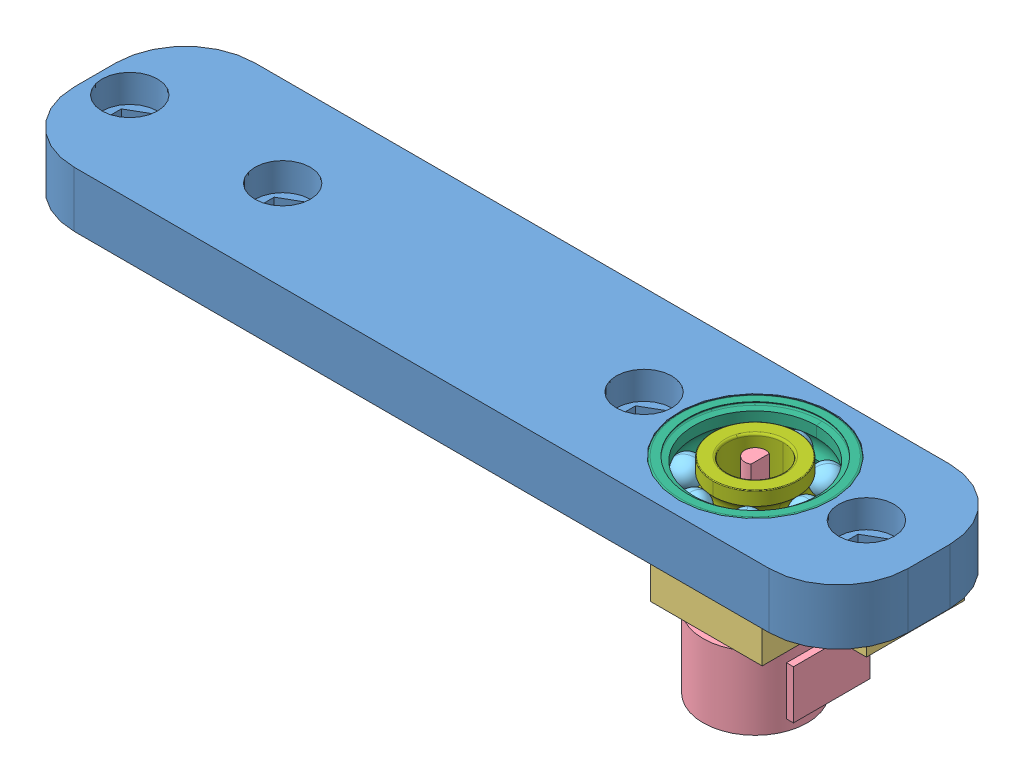
SolidWorks assembly sub_assy_robot_arm_link1, configuration Default. Lengths in mm.
Overall size (120 31 26).
14 component instances, 7 part files, 11 mates.
Components (placement in the parent):
- 2D_robotArm_link1_v1-1: 2D_robotArm_link1_v1 [Default] at origin size (120 8 26)
- robot_arm_link_bearing_insert_mk1-1: robot_arm_link_bearing_insert_mk1 [Default] at (-44 0 0) x (1 0 0) z (0 0 -1) size (30 9 11.5)
- DfRobot_stepper_FIT0503_mount_v3-1: DfRobot_stepper_FIT0503_mount_v3 [Default] at (35 0 0) x (1 0 0) z (0 0 -1) size (46.1 10.6 14.1)
- Df_Robot_stepper_FIT0503-1: Df_Robot_stepper_FIT0503 [Default] at (35 -2 0) x (-1 0 0) z (0 0 1) size (16 31 15.5)
- 608_Z-1: 608_Z [Default] at (35 8 0) x (0 -1 0) z (0 0 1) size (7 22 22)
  - 608_Z_11-1: 608_Z_11 [Default] x (1 0 0) z (0 -0.781831 0.62349) size (3.97 3.97 3.97)
  - 608_Z_11-2: 608_Z_11 [Default] x (1 0 0) z (0 -0.974928 -0.222521) size (3.97 3.97 3.97)
  - 608_Z_11-3: 608_Z_11 [Default] x (1 0 0) z (0 -0.433884 -0.900969) size (3.97 3.97 3.97)
  - 608_Z_11-4: 608_Z_11 [Default] x (1 0 0) z (0 0.433884 -0.900969) size (3.97 3.97 3.97)
  - 608_Z_11-5: 608_Z_11 [Default] x (1 0 0) z (0 0.974928 -0.222521) size (3.97 3.97 3.97)
  - 608_Z_11-6: 608_Z_11 [Default] x (1 0 0) z (0 0.781831 0.62349) size (3.97 3.97 3.97)
  - 608_Z_11-7: 608_Z_11 [Default] at origin size (3.97 3.97 3.97)
  - 608_Z_19-1: 608_Z_19 [Default] at origin size (7 22 22)
  - 608_Z_21-1: 608_Z_21 [Default] at origin size (7 19.2 19.2)
Mates (geometry in assembly coordinates):
- Coincident1: coincident aligned: line of 2D_robotArm_link1_v1-1 through (4 -33 4) axis (0 0 1); line of robot_arm_link_bearing_insert_mk1-1 through (2 -33 -2) axis (0 0 1)
- Coincident2: coincident aligned: line of 2D_robotArm_link1_v1-1 through (4 -55 4) axis (0 0 1); line of robot_arm_link_bearing_insert_mk1-1 through (2 -55 -2) axis (0 0 1)
- Coincident3: coincident anti-aligned: plane of 2D_robotArm_link1_v1-1 through (0 0 0) normal (0 -1 0); plane of robot_arm_link_bearing_insert_mk1-1 through (-44 0 0) normal (0 1 0)
- Coincident11: coincident: line of assembly; line of assembly; axis of 2D_robotArm_link1_v1-1 through (4 51 4) axis (0 0 1); axis of DfRobot_stepper_FIT0503_mount_v3-1 through (51 -2 0) axis (0 1 0)
- Coincident12: coincident: plane of 2D_robotArm_link1_v1-1 through (0 0 0) normal (0 -1 0); plane of DfRobot_stepper_FIT0503_mount_v3-1 through (35 0 0) normal (0 1 0)
- Coincident14: coincident aligned: line of 2D_robotArm_link1_v1-1 through (1.8 19 0) axis (0 0 1); line of DfRobot_stepper_FIT0503_mount_v3-1 through (19 -2 0) axis (0 1 0)
- Coincident15: coincident: line of assembly; line of assembly; axis of DfRobot_stepper_FIT0503_mount_v3-1 through (39.5 -2 0) axis (0 1 0); axis of Df_Robot_stepper_FIT0503-1 through (39.5 -35.2356 0) axis (0 1 0)
- Coincident16: coincident: line of assembly; line of assembly; axis of DfRobot_stepper_FIT0503_mount_v3-1 through (30.5 -2 0) axis (0 1 0); axis of Df_Robot_stepper_FIT0503-1 through (30.5 -4 0) axis (0 1 0)
- Coincident17: coincident anti-aligned: plane of DfRobot_stepper_FIT0503_mount_v3-1 through (35 -2 0) normal (0 -1 0); plane of Df_Robot_stepper_FIT0503-1 through (35 -2 0) normal (0 1 0)
- Coincident18: coincident: line of 2D_robotArm_link1_v1-1 through (7 35 1) axis (0 0 1); line of ? through (15.5088 35 12.8696) axis (0 0 -1)
- Coincident19: coincident anti-aligned: plane of 2D_robotArm_link1_v1-1 through (0 1 0) normal (0 1 0); plane of 608_Z-1/608_Z_19-1 through (44.6 1 0) normal (0 -1 0)
